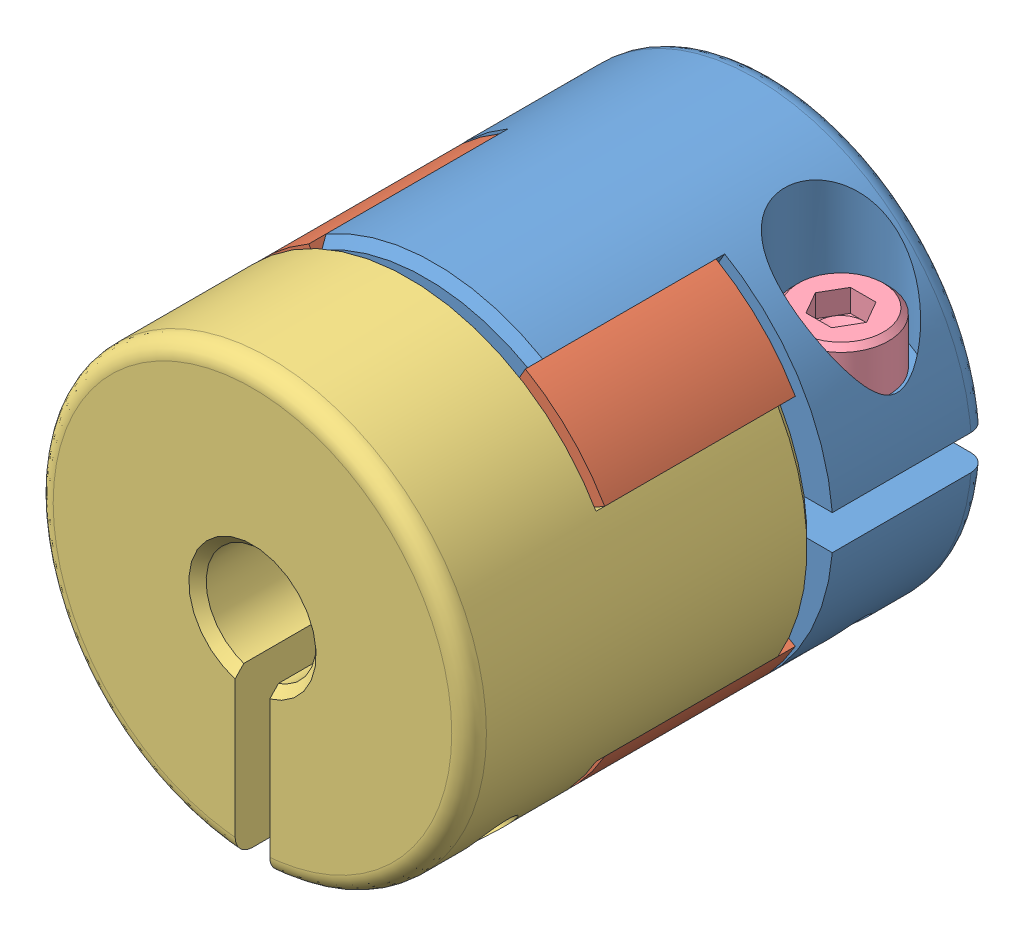
SolidWorks assembly Montagem5, configuration Valor predeterminado. Lengths in mm.
Overall size (34.15 34.15 30.11).
5 component instances, 4 part files, 10 mates.
Components (placement in the parent):
- Lateral Al furo=10-1: Lateral Al furo=10 [Valor predeterminado] at (-10.0281 -0.8891 15.0452) size (25.02 25 20.06)
- Aranha D=25mm-1: Aranha D=25mm [Valor predeterminado] at (-10.0281 -0.8891 30.0452) x (0.866025 -0.5 0) z (0 0 1) size (25 25 14)
- Lateral Al furo=6,35-1: Lateral Al furo=6,35 [Valor predeterminado] at (-10.0281 -0.8891 45.0452) x (0 -1 0) z (0 0 -1) size (25.02 25 20.06)
- Parafuso allen M3x10-1: Parafuso allen M3x10 [B18.3.1M - 3 x 0.5 x 10 Hex SHCS -- 10CHX] at (-1.5682 6.1109 19.5452) x (0 -1 0) z (0 0 1) size (13 5.5 5.5)
- Parafuso allen M3x10-2: Parafuso allen M3x10 [B18.3.1M - 3 x 0.5 x 10 Hex SHCS -- 10CHX] at (-17.0281 -9.3491 40.5452) size (13 5.5 5.5)
Mates (geometry in assembly coordinates):
- Concêntrico1: concentric aligned: cylinder of Lateral Al furo=10-1 through (-10.0281 -0.8891 35.0452) axis (0 0 -1) radius 5; cylinder of Aranha D=25mm-1 through (-10.0281 -0.8891 35.5452) axis (0 0 -1) radius 4.5
- Concêntrico2: concentric aligned: cylinder of Lateral Al furo=10-1 through (-16.3921 5.4748 23.0452) axis (0 0 1) radius 1.5; cylinder of Aranha D=25mm-1 through (-16.3921 5.4748 23.0452) axis (0 0 1) radius 1.5
- Coincidente1: coincident anti-aligned: plane of Lateral Al furo=10-1 through (-16.3921 5.4748 23.0452) normal (0 0 1); plane of Aranha D=25mm-1 through (-16.3921 5.4748 23.0452) normal (0 0 -1)
- Concêntrico3: concentric anti-aligned: cylinder of Lateral Al furo=10-1 through (-10.0281 -0.8891 35.0452) axis (0 0 -1) radius 12.5; cylinder of Lateral Al furo=6,35-1 through (-10.0281 -0.8891 25.0452) axis (0 0 1) radius 12.5
- Concêntrico4: concentric aligned: cylinder of Aranha D=25mm-1 through (-16.3921 5.4748 37.0452) axis (0 0 -1) radius 1.5; cylinder of Lateral Al furo=6,35-1 through (-16.3921 5.4748 37.0452) axis (0 0 -1) radius 1.5
- Coincidente2: coincident anti-aligned: plane of Aranha D=25mm-1 through (-16.3921 5.4748 37.0452) normal (0 0 1); plane of Lateral Al furo=6,35-1 through (-16.3921 5.4748 37.0452) normal (0 0 -1)
- Concêntrico51: concentric aligned: cylinder of Lateral Al furo=10-1 through (-1.5682 -13.3901 19.5452) axis (0 1 0) radius 1.5; cylinder of Parafuso allen M3x10-1 through (-1.5682 37.8609 19.5452) axis (0 1 0) radius 2.75
- Coincidente31: coincident anti-aligned: plane of Lateral Al furo=10-1 through (-1.5682 3.1109 19.5452) normal (0 1 0); plane of Parafuso allen M3x10-1 through (1.1818 3.1109 19.5452) normal (0 -1 0)
- Concêntrico61: concentric: cylinder of Lateral Al furo=6,35-1 through (2.4729 -9.3491 40.5452) axis (-1 0 0) radius 1.5; cylinder of Parafuso allen M3x10-2 through (-86.1995 -27.9446 38.6827) axis (-1 0 0) radius 2.75
- Coincidente41: coincident: plane of Lateral Al furo=6,35-1 through (-14.0281 -9.3491 40.5452) normal (-1 0 0); plane of Parafuso allen M3x10-2 through (-51.4495 -25.1946 38.6827) normal (1 0 0)
